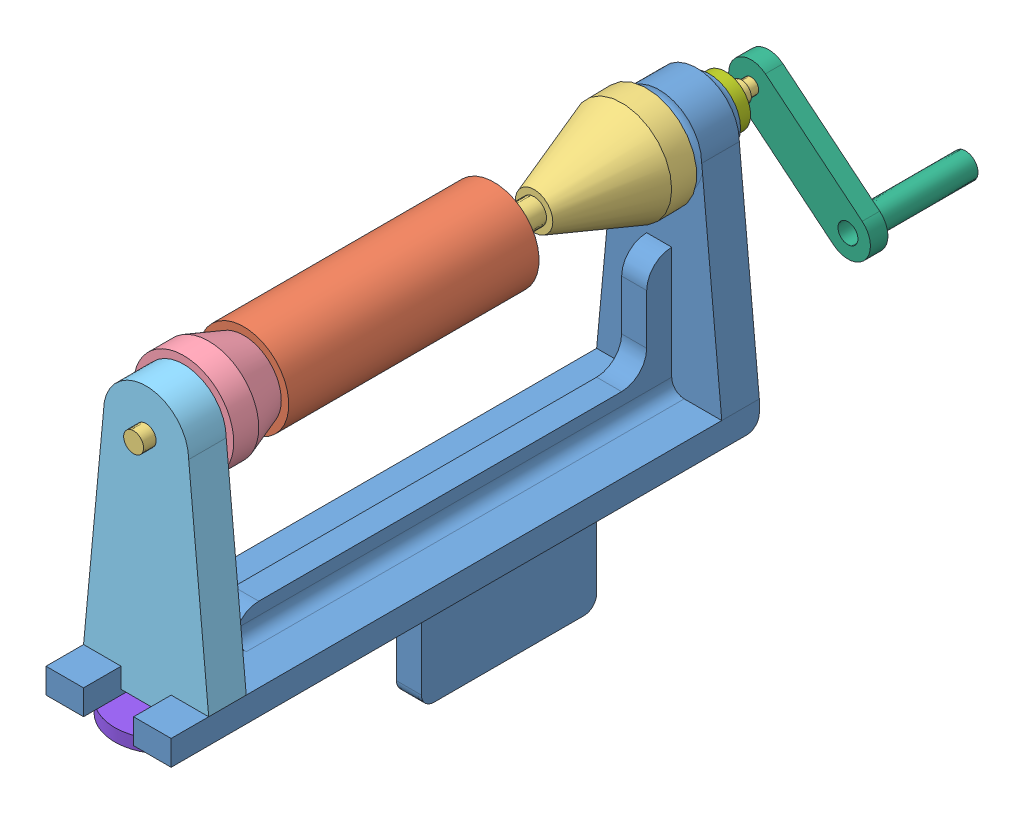
SolidWorks assembly Assem2, configuration Default. Lengths in mm.
Overall size (79.59 173.26 303.73).
9 component instances, 9 part files, 17 mates.
Components (placement in the parent):
- e-1: e [Default] at (69.9816 79.1897 89.7937) size (50 162 240)
- c-1: c [Default] at (69.9816 174.1897 170.7937) x (-0.899662 0.436586 0) z (0 0 1) size (36 36 100)
- d-1: d [Default] at (69.9816 174.1897 314.7937) x (0 0 -1) z (-0.880879 -0.473341 0) size (253.73 40 40)
- b-1: b [Default] at (69.9816 174.1897 294.7937) x (0 0 -1) z (-0.73779 0.67503 0) size (45 40 40)
- a-1: a [Default] at (69.9816 81.1897 294.7937) size (50 110 15)
- g-1: g [Default] at (89.3165 158.3416 68.0597) x (0.773397 -0.633922 0) z (0.633922 0.773397 0) size (68 47 18)
- f-1: f [Default] at (69.9816 174.1897 78.2976) size (20 20 5)
- h-1: h [Default] at (69.9816 74.1897 302.2937) size (40 5 40)
- j-1: j [Default] at (69.9816 74.1897 302.2937) x (1 0 0) z (0 -1 0) size (20.32 16 33)
Mates (geometry in assembly coordinates):
- Concentric1: concentric aligned: circle of e-1; cylinder of d-1 through (69.9816 174.1897 314.7937) axis (0 0 1) radius 5
- Coincident1: coincident anti-aligned: plane of e-1 through (69.9816 174.1897 109.7937) normal (0 0 1); plane of d-1 through (52.364 164.7228 109.7937) normal (0 0 -1)
- Concentric2: concentric aligned: circle of c-1; circle of d-1
- Concentric4: concentric aligned: circle of c-1; circle of b-1
- Coincident2: coincident: circle of c-1; cone of b-1 through (69.9816 174.1897 284.7937) axis (0 0 -1)
- Lock1: lock: unknown of c-1; unknown of b-1
- Coincident4: coincident aligned: plane of d-1 through (66.4581 172.2963 294.7937) normal (0 0 1); plane of b-1 through (75.0443 179.7231 294.7937) normal (0 0 1)
- Concentric6: concentric aligned: cylinder of d-1 through (69.9816 174.1897 314.7937) axis (0 0 1) radius 4; circle of b-1
- Coincident6: coincident anti-aligned: plane of e-1 through (44.9816 89.1897 324.7937) normal (0 1 0); plane of a-1 through (79.9816 89.1897 309.7937) normal (0 -1 0)
- Coincident7: coincident anti-aligned: plane of b-1 through (75.0443 179.7231 294.7937) normal (0 0 1); plane of a-1 through (69.9816 174.1897 294.7937) normal (0 0 -1)
- Coincident8: coincident anti-aligned: circle of d-1; circle of g-1
- Coincident9: coincident aligned: cylinder of d-1 through (69.9816 174.1897 314.7937) axis (0 0 1) radius 4; circle of f-1
- Coincident10: coincident anti-aligned: plane of d-1 through (65.5772 171.823 83.2976) normal (0 0 -1); plane of f-1 through (69.9816 174.1897 83.2976) normal (0 0 1)
- Concentric7: concentric anti-aligned: circle of a-1; circle of h-1
- Coincident11: coincident anti-aligned: plane of e-1 through (44.9816 79.1897 104.7937) normal (0 -1 0); plane of h-1 through (69.9816 79.1897 302.2937) normal (0 1 0)
- Concentric8: concentric anti-aligned: circle of h-1; cylinder of j-1 through (69.9816 99.1897 302.2937) axis (0 -1 0) radius 4
- Coincident12: coincident anti-aligned: plane of h-1 through (69.9816 74.1897 302.2937) normal (0 -1 0); plane of j-1 through (69.9816 74.1897 302.2937) normal (0 1 0)
